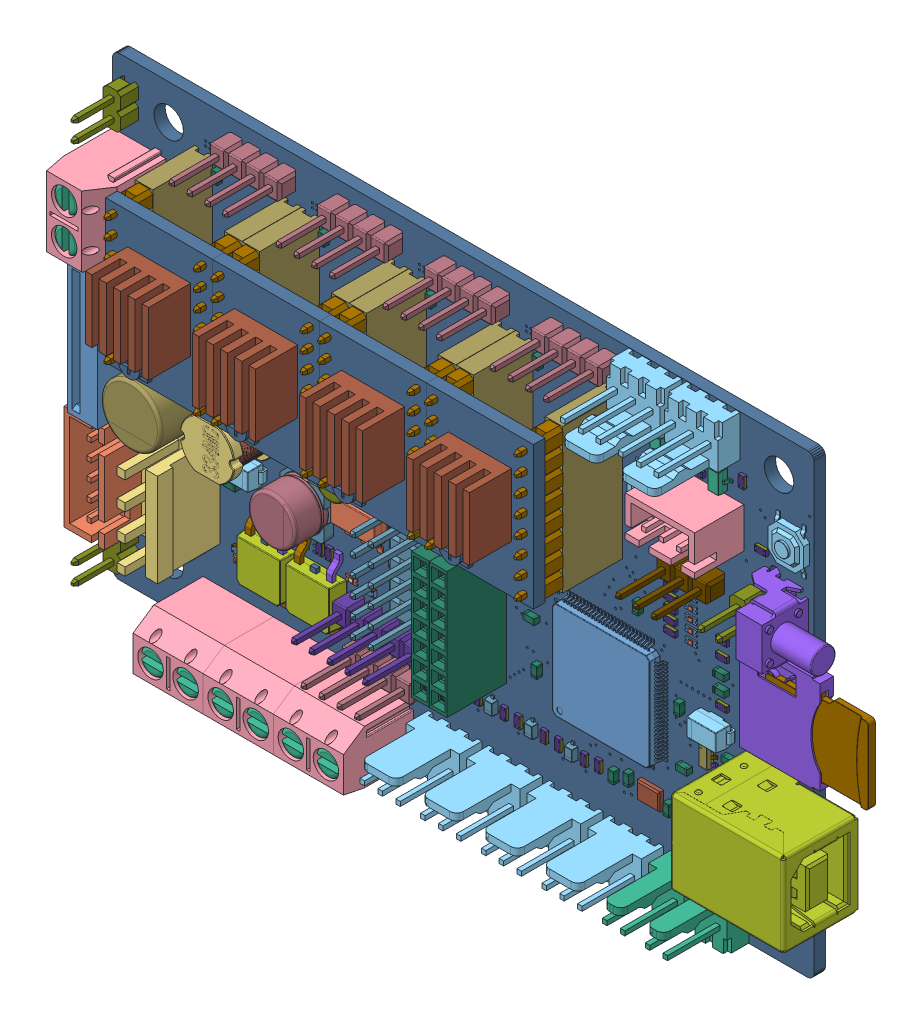
SolidWorks assembly C3D Mini v2 ASMB, configuration Default. Lengths in mm.
Overall size (109.57 66.19 23.09).
293 component instances, 83 part files, 12 mates.
Components (placement in the parent):
- C3D Mini v2 SMD-1: C3D Mini v2 SMD [Default] at (100 0.95 0) size (90.6 49.98 10.5)
  - Cut-Extrude1-1: Cut-Extrude1 [Default] at (-28.841 21.832 0) x (0 1 0) z (1 0 0) size (16.02 1.55 16.02)
  - Fillet3-1: Fillet3 [Default] at (-64.008 24.638 0) x (0 1 0) z (1 0 0) size (7.02 1.8 6.5)
  - LPattern4-1: LPattern4 [Default] at (-50.673 18.415 0) x (1 0 0) z (0 -1 0) size (2.9 1.5 2.82)
  - Cut-Extrude1-1-1: Cut-Extrude1-1 [Default] at (-70.993 28.702 0) x (0 -1 0) z (-1 0 0) size (4.9 1.5 6.03)
  - Mirror2-1: Mirror2 [Default] at (-23.241 47.879 0) x (0 1 0) z (0 0 1) size (6.5 5.08 1.52)
  - Mirror2-2: Mirror2 [Default] at (-3.187 51.423 0) x (0 1 0) z (0 0 1) size (6.5 5.08 1.52)
  - CirPattern1-1: CirPattern1 [Default] at (-12.942 54.979 0) x (0 -1 0) z (-1 0 0) size (2.9 1.5 2.82)
  - CirPattern1-2: CirPattern1 [Default] at (-21.197 54.979 0) x (0 -1 0) z (-1 0 0) size (2.9 1.5 2.82)
  - Solid1-1: Solid1 [Default] at (-67.56 17.327 0) x (-1 0 0) z (0 0 1) size (6.68 6.2 2.38)
  - Solid1-2: Solid1 [Default] at (-74.545 17.327 0) x (-1 0 0) z (0 0 1) size (6.68 6.2 2.38)
  - Solid2-1: Solid2 [Default] at (-67.56 17.327 0) x (-1 0 0) z (0 0 1) size (0.85 3.15 1.55)
  - Solid2-2: Solid2 [Default] at (-74.545 17.327 0) x (-1 0 0) z (0 0 1) size (0.85 3.15 1.55)
  - Solid3-1: Solid3 [Default] at (-74.545 17.327 0) x (-1 0 0) z (0 0 1) size (0.85 3.15 1.55)
  - Solid3-2: Solid3 [Default] at (-67.56 17.327 0) x (-1 0 0) z (0 0 1) size (0.85 3.15 1.55)
  - Solid4-1: Solid4 [Default] at (-74.545 17.327 0) x (-1 0 0) z (0 0 1) size (0.85 0.8 0.54)
  - Solid4-2: Solid4 [Default] at (-67.56 17.327 0) x (-1 0 0) z (0 0 1) size (0.85 0.8 0.54)
  - Solid5-1: Solid5 [Default] at (-74.545 17.327 0) x (-1 0 0) z (0 0 1) size (5.45 6.25 0.55)
  - Solid5-2: Solid5 [Default] at (-67.56 17.327 0) x (-1 0 0) z (0 0 1) size (5.45 6.25 0.55)
  - Solid1-1-1: Solid1-1 [Default] at (-86.995 33.93 -0.05) x (0 -1 0) z (0 0 1) size (8.5 8.5 10)
  - Solid2-1-1: Solid2-1 [Default] at (-86.995 33.93 -0.05) x (0 -1 0) z (0 0 1) size (8.5 8.5 1.4)
  - Solid3-1-1: Solid3-1 [Default] at (-86.995 33.93 -0.05) x (0 -1 0) z (0 0 1) size (3.45 1 0.7)
  - Solid4-1-1: Solid4-1 [Default] at (-86.995 33.93 -0.05) x (0 -1 0) z (0 0 1) size (3.45 1 0.7)
  - Solid1-2-1: Solid1-2 [Default] at (-61.827 31.242 -0.05) x (-1 0 0) z (0 0 1) size (4.5 4.5 5)
  - Solid2-2-1: Solid2-2 [Default] at (-61.827 31.242 -0.05) x (-1 0 0) z (0 0 1) size (4.5 4.5 1.4)
  - Solid3-2-1: Solid3-2 [Default] at (-61.827 31.242 -0.05) x (-1 0 0) z (0 0 1) size (2.25 0.75 0.7)
  - Solid4-2-1: Solid4-2 [Default] at (-61.827 31.242 -0.05) x (-1 0 0) z (0 0 1) size (2.25 0.75 0.7)
  - _I2-1: _I2 [Default] at (-62.3815 42.0396 0) x (1 0 0) z (0 0 -1) size (6.4 7.16 4.3)
  - _I3-1: _I3 [Default] at (-62.3815 42.0396 0) x (1 0 0) z (0 0 -1) size (7.69 7 7.52)
  - _I4-1: _I4 [Default] at (-62.3815 42.0396 0) x (1 0 0) z (0 0 -1) size (2.09 0.2 5.4)
  - Mirror1-1: Mirror1 [Default] at (-80.403 22.594 0) x (1 0 0) z (0 -1 0) size (5.2 2.4 2.75)
  - Mirror1-2: Mirror1 [Default] at (-72.517 32.766 0) x (-1 0 0) z (0 1 0) size (5.2 2.4 2.75)
  - Mirror1-3: Mirror1 [Default] at (-13.716 23.749 0) x (-1 0 0) z (0 1 0) size (5.2 2.4 2.75)
  - NONE-1: NONE [Default] at (-14.871 21.25 0) x (1 0 0) z (0 -1 0) size (0.54 0.52 0.44)
  - Cut-Extrude4[6]-1: Cut-Extrude4[6] [Default] at (-14.871 21.25 0) x (1 0 0) z (0 -1 0) size (0.54 0.52 0.44)
  - Cut-Extrude4[4]-1: Cut-Extrude4[4] [Default] at (-14.871 21.25 0) x (1 0 0) z (0 -1 0) size (0.54 0.52 0.44)
  - Cut-Extrude4[3]-1: Cut-Extrude4[3] [Default] at (-14.871 21.25 0) x (1 0 0) z (0 -1 0) size (0.54 0.52 0.44)
  - Cut-Extrude4[1]-1: Cut-Extrude4[1] [Default] at (-14.871 21.25 0) x (1 0 0) z (0 -1 0) size (0.54 0.52 0.44)
  - Cut-Extrude4[5]-1: Cut-Extrude4[5] [Default] at (-14.871 21.25 0) x (1 0 0) z (0 -1 0) size (0.54 0.52 0.44)
  - Fillet1-1: Fillet1 [Default] at (-14.871 21.25 0) x (1 0 0) z (0 -1 0) size (1.31 0.94 2.91)
  - Solid1-3-1: Solid1-3 [Default] at (-74.432 22.606 -0.05) size (6.8 6.8 5)
  - Solid2-3-1: Solid2-3 [Default] at (-74.432 22.606 -0.05) size (6.8 6.8 1.4)
  - Solid3-3-1: Solid3-3 [Default] at (-74.432 22.606 -0.05) size (3 0.75 0.7)
  - Solid4-3-1: Solid4-3 [Default] at (-74.432 22.606 -0.05) size (3 0.75 0.7)
  - Split Line4-1: Split Line4 [Default] at (-17.399 39.243 0) x (1 0 0) z (0 -1 0) size (1.6 0.18 0.8)
  - Boss-Extrude2-1: Boss-Extrude2 [Default] at (-17.399 39.243 0) x (1 0 0) z (0 -1 0) size (0.6 0.1 0.5)
  - Split Line4-1-1: Split Line4-1 [Default] at (-17.399 32.258 0) x (1 0 0) z (0 -1 0) size (1.6 0.18 0.8)
  - Split Line4-1-2: Split Line4-1 [Default] at (-17.399 33.655 0) x (1 0 0) z (0 -1 0) size (1.6 0.18 0.8)
  - Split Line4-1-3: Split Line4-1 [Default] at (-17.399 35.052 0) x (1 0 0) z (0 -1 0) size (1.6 0.18 0.8)
  - Split Line4-1-4: Split Line4-1 [Default] at (-17.399 37.846 0) x (1 0 0) z (0 -1 0) size (1.6 0.18 0.8)
  - Split Line4-1-5: Split Line4-1 [Default] at (-17.399 36.449 0) x (1 0 0) z (0 -1 0) size (1.6 0.18 0.8)
  - Split Line4-1-6: Split Line4-1 [Default] at (-8.521 39.993 0) x (1 0 0) z (0 -1 0) size (1.6 0.18 0.8)
  - Boss-Extrude2-1-1: Boss-Extrude2-1 [Default] at (-8.521 39.993 0) x (1 0 0) z (0 -1 0) size (0.6 0.1 0.5)
  - Boss-Extrude2-1-2: Boss-Extrude2-1 [Default] at (-17.399 36.449 0) x (1 0 0) z (0 -1 0) size (0.6 0.1 0.5)
  - Boss-Extrude2-1-3: Boss-Extrude2-1 [Default] at (-17.399 37.846 0) x (1 0 0) z (0 -1 0) size (0.6 0.1 0.5)
  - Boss-Extrude2-1-4: Boss-Extrude2-1 [Default] at (-17.399 35.052 0) x (1 0 0) z (0 -1 0) size (0.6 0.1 0.5)
  - Boss-Extrude2-1-5: Boss-Extrude2-1 [Default] at (-17.399 33.655 0) x (1 0 0) z (0 -1 0) size (0.6 0.1 0.5)
  - Boss-Extrude2-1-6: Boss-Extrude2-1 [Default] at (-17.399 32.258 0) x (1 0 0) z (0 -1 0) size (0.6 0.1 0.5)
  - Boss-Extrude3-1: Boss-Extrude3 [Default] at (-49.415 44.184 0) x (-1 0 0) z (0 1 0) size (7 7.7 6.6)
  - Boss-Extrude3-2: Boss-Extrude3 [Default] at (-64.655 44.184 0) x (-1 0 0) z (0 1 0) size (7 7.7 6.6)
  - Boss-Extrude3-3: Boss-Extrude3 [Default] at (-34.175 44.184 0) x (-1 0 0) z (0 1 0) size (7 7.7 6.6)
  - Boss-Extrude3-4: Boss-Extrude3 [Default] at (-79.895 44.184 0) x (-1 0 0) z (0 1 0) size (7 7.7 6.6)
  - Solid1-4-1: Solid1-4 [Default] at (-13.686 12.407 0) x (-1 0 0) z (0 0 1) size (0.5 0.45 0.55)
  - Solid2-4-1: Solid2-4 [Default] at (-13.686 12.407 0) x (-1 0 0) z (0 0 1) size (0.5 0.45 0.55)
  - Solid3-4-1: Solid3-4 [Default] at (-13.686 12.407 0) x (-1 0 0) z (0 0 1) size (0.5 0.45 0.55)
  - Solid4-4-1: Solid4-4 [Default] at (-13.686 12.407 0) x (-1 0 0) z (0 0 1) size (0.5 0.45 0.55)
  - Solid5-1-1: Solid5-1 [Default] at (-13.686 12.407 0) x (-1 0 0) z (0 0 1) size (3.35 1.69 0.49)
  - Solid6-1: Solid6 [Default] at (-13.686 12.407 0) x (-1 0 0) z (0 0 1) size (3.18 1.09 0.08)
  - Solid7-1: Solid7 [Default] at (-13.686 12.407 0) x (-1 0 0) z (0 0 1) size (0.72 0.45 0.55)
  - Solid8-1: Solid8 [Default] at (-13.686 12.407 0) x (-1 0 0) z (0 0 1) size (0.72 0.45 0.55)
  - Solid9-1: Solid9 [Default] at (-13.686 12.407 0) x (-1 0 0) z (0 0 1) size (0.73 0.45 0.55)
  - Solid10-1: Solid10 [Default] at (-13.686 12.407 0) x (-1 0 0) z (0 0 1) size (0.73 0.45 0.55)
  - Boss-Extrude2-2-1: Boss-Extrude2-2 [Default] at (-51.423 10.299 0) x (0 -1 0) z (-1 0 0) size (2.5 0.8 1.25)
  - Boss-Extrude2-2-2: Boss-Extrude2-2 [Default] at (-45.708 10.299 0) x (0 -1 0) z (-1 0 0) size (2.5 0.8 1.25)
  - Boss-Extrude2-2-3: Boss-Extrude2-2 [Default] at (-34.278 10.299 0) x (0 -1 0) z (-1 0 0) size (2.5 0.8 1.25)
  - Boss-Extrude2-2-4: Boss-Extrude2-2 [Default] at (-39.993 10.299 0) x (0 -1 0) z (-1 0 0) size (2.5 0.8 1.25)
  - Mirror1-1-1: Mirror1-1 [Default] at (-12.839 30.722 0) x (1 0 0) z (0 -1 0) size (1.6 0.82 0.82)
  - Mirror1-1-2: Mirror1-1 [Default] at (-18.796 23.622 0) x (0 1 0) z (1 0 0) size (1.6 0.82 0.82)
  - Mirror1-1-3: Mirror1-1 [Default] at (-20.32 10.414 0) x (0 1 0) z (1 0 0) size (1.6 0.82 0.82)
  - Mirror1-1-4: Mirror1-1 [Default] at (-26.047 11.291 0) x (0 1 0) z (1 0 0) size (1.6 0.82 0.82)
  - Mirror1-1-5: Mirror1-1 [Default] at (-13.589 7.874 0) x (0 -1 0) z (-1 0 0) size (1.6 0.82 0.82)
  - Mirror1-1-6: Mirror1-1 [Default] at (-61.2895 27.8645 0) x (0 1 0) z (1 0 0) size (1.6 0.82 0.82)
  - Mirror1-1-7: Mirror1-1 [Default] at (-28.182 10.553 0) x (0 1 0) z (1 0 0) size (1.6 0.82 0.82)
  - Mirror1-1-8: Mirror1-1 [Default] at (-53.479 39.485 0) x (1 0 0) z (0 -1 0) size (1.6 0.82 0.82)
  - Mirror1-1-9: Mirror1-1 [Default] at (-39.128 18.0982 0) x (0 1 0) z (1 0 0) size (1.6 0.82 0.82)
  - Mirror1-1-10: Mirror1-1 [Default] at (-15.621 7.874 0) x (0 -1 0) z (-1 0 0) size (1.6 0.82 0.82)
  - Mirror1-1-11: Mirror1-1 [Default] at (-11.684 14.605 0) x (1 0 0) z (0 -1 0) size (1.6 0.82 0.82)
  - Mirror1-1-12: Mirror1-1 [Default] at (-69.481 56.249 0) x (0 -1 0) z (-1 0 0) size (1.6 0.82 0.82)
  - Mirror1-1-13: Mirror1-1 [Default] at (-18.796 10.668 0) x (0 1 0) z (1 0 0) size (1.6 0.82 0.82)
  - Mirror1-1-14: Mirror1-1 [Default] at (-39.89 24.1688 0) x (1 0 0) z (0 -1 0) size (1.6 0.82 0.82)
  - Mirror1-1-15: Mirror1-1 [Default] at (-33.6035 33.135 0) x (0 1 0) z (1 0 0) size (1.6 0.82 0.82)
  - Mirror1-1-16: Mirror1-1 [Default] at (-11.684 20.701 0) x (1 0 0) z (0 -1 0) size (1.6 0.82 0.82)
  - Mirror1-1-17: Mirror1-1 [Default] at (-18.149 16.4472 0) x (1 0 0) z (0 -1 0) size (1.6 0.82 0.82)
  - Mirror1-1-18: Mirror1-1 [Default] at (-82.55 19.304 0) x (1 0 0) z (0 -1 0) size (1.6 0.82 0.82)
  - Mirror1-1-19: Mirror1-1 [Default] at (-24.7135 33.135 0) x (0 1 0) z (1 0 0) size (1.6 0.82 0.82)
  - Mirror1-1-20: Mirror1-1 [Default] at (-50.8 15.494 0) x (1 0 0) z (0 -1 0) size (1.6 0.82 0.82)
  - Mirror1-1-21: Mirror1-1 [Default] at (-39.001 56.249 0) x (0 -1 0) z (-1 0 0) size (1.6 0.82 0.82)
  - Mirror1-1-22: Mirror1-1 [Default] at (-83.959 39.485 0) x (1 0 0) z (0 -1 0) size (1.6 0.82 0.82)
  - Mirror1-1-23: Mirror1-1 [Default] at (-84.721 56.249 0) x (0 -1 0) z (-1 0 0) size (1.6 0.82 0.82)
  - Mirror1-1-24: Mirror1-1 [Default] at (-68.719 39.485 0) x (1 0 0) z (0 -1 0) size (1.6 0.82 0.82)
  - Mirror1-1-25: Mirror1-1 [Default] at (-12.839 28.69 0) x (1 0 0) z (0 -1 0) size (1.6 0.82 0.82)
  - Mirror1-1-26: Mirror1-1 [Default] at (-38.239 39.485 0) x (1 0 0) z (0 -1 0) size (1.6 0.82 0.82)
  - Mirror1-1-27: Mirror1-1 [Default] at (-54.241 56.249 0) x (0 -1 0) z (-1 0 0) size (1.6 0.82 0.82)
  - Boss-Extrude3-1-1: Boss-Extrude3-1 [Default] at (-34.81 39.885 0) x (1 0 0) z (0 -1 0) size (1.54 0.39 0.8)
  - Boss-Extrude3-1-2: Boss-Extrude3-1 [Default] at (-12.839 27.058 0) x (1 0 0) z (0 -1 0) size (1.54 0.39 0.8)
  - Boss-Extrude3-1-3: Boss-Extrude3-1 [Default] at (-47.213 10.299 0) x (0 -1 0) z (-1 0 0) size (1.54 0.39 0.8)
  - Boss-Extrude3-1-4: Boss-Extrude3-1 [Default] at (-80.53 39.885 0) x (1 0 0) z (0 -1 0) size (1.54 0.39 0.8)
  - Boss-Extrude3-1-5: Boss-Extrude3-1 [Default] at (-20.193 39.643 0) x (1 0 0) z (0 -1 0) size (1.54 0.39 0.8)
  - Boss-Extrude3-1-6: Boss-Extrude3-1 [Default] at (-12.839 33.154 0) x (1 0 0) z (0 -1 0) size (1.54 0.39 0.8)
  - Boss-Extrude3-1-7: Boss-Extrude3-1 [Default] at (-9.5822 55.88 0) x (0 -1 0) z (-1 0 0) size (1.54 0.39 0.8)
  - Boss-Extrude3-1-8: Boss-Extrude3-1 [Default] at (-49.384 22.225 0) x (0 -1 0) z (-1 0 0) size (1.54 0.39 0.8)
  - Boss-Extrude3-1-9: Boss-Extrude3-1 [Default] at (-12.839 35.186 0) x (1 0 0) z (0 -1 0) size (1.54 0.39 0.8)
  - Boss-Extrude3-1-10: Boss-Extrude3-1 [Default] at (-68.434 17.526 0) x (0 -1 0) z (-1 0 0) size (1.54 0.39 0.8)
  - Boss-Extrude3-1-11: Boss-Extrude3-1 [Default] at (-20.193 38.246 0) x (1 0 0) z (0 -1 0) size (1.54 0.39 0.8)
  - Boss-Extrude3-1-12: Boss-Extrude3-1 [Default] at (-46.621 39.25 0) x (1 0 0) z (0 -1 0) size (1.54 0.39 0.8)
  - Boss-Extrude3-1-13: Boss-Extrude3-1 [Default] at (-61.861 39.25 0) x (1 0 0) z (0 -1 0) size (1.54 0.39 0.8)
  - Boss-Extrude3-1-14: Boss-Extrude3-1 [Default] at (-41.498 10.299 0) x (0 -1 0) z (-1 0 0) size (1.54 0.39 0.8)
  - Boss-Extrude3-1-15: Boss-Extrude3-1 [Default] at (-31.381 39.25 0) x (1 0 0) z (0 -1 0) size (1.54 0.39 0.8)
  - Boss-Extrude3-1-16: Boss-Extrude3-1 [Default] at (-52.928 10.299 0) x (0 -1 0) z (-1 0 0) size (1.54 0.39 0.8)
  - Boss-Extrude3-1-17: Boss-Extrude3-1 [Default] at (-49.245 10.299 0) x (0 -1 0) z (-1 0 0) size (1.54 0.39 0.8)
  - Boss-Extrude3-1-18: Boss-Extrude3-1 [Default] at (-24.499 54.363 0) x (1 0 0) z (0 -1 0) size (1.54 0.39 0.8)
  - Boss-Extrude3-1-19: Boss-Extrude3-1 [Default] at (-76.7271 17.526 0) x (0 -1 0) z (-1 0 0) size (1.54 0.39 0.8)
  - Boss-Extrude3-1-20: Boss-Extrude3-1 [Default] at (-20.193 32.658 0) x (1 0 0) z (0 -1 0) size (1.54 0.39 0.8)
  - Boss-Extrude3-1-21: Boss-Extrude3-1 [Default] at (-11.684 12.973 0) x (1 0 0) z (0 -1 0) size (1.54 0.39 0.8)
  - Boss-Extrude3-1-22: Boss-Extrude3-1 [Default] at (-6.489 44.965 0) x (1 0 0) z (0 -1 0) size (1.54 0.39 0.8)
  - Boss-Extrude3-1-23: Boss-Extrude3-1 [Default] at (-20.193 35.452 0) x (1 0 0) z (0 -1 0) size (1.54 0.39 0.8)
  - Boss-Extrude3-1-24: Boss-Extrude3-1 [Default] at (-20.193 34.055 0) x (1 0 0) z (0 -1 0) size (1.54 0.39 0.8)
  - Boss-Extrude3-1-25: Boss-Extrude3-1 [Default] at (-24.499 56.395 0) x (1 0 0) z (0 -1 0) size (1.54 0.39 0.8)
  - Boss-Extrude3-1-26: Boss-Extrude3-1 [Default] at (-22.352 44.088 0) x (1 0 0) z (0 -1 0) size (1.54 0.39 0.8)
  - Boss-Extrude3-1-27: Boss-Extrude3-1 [Default] at (-32.1 10.299 0) x (0 -1 0) z (-1 0 0) size (1.54 0.39 0.8)
  - Boss-Extrude3-1-28: Boss-Extrude3-1 [Default] at (-65.29 39.885 0) x (1 0 0) z (0 -1 0) size (1.54 0.39 0.8)
  - Boss-Extrude3-1-29: Boss-Extrude3-1 [Default] at (-50.05 39.885 0) x (1 0 0) z (0 -1 0) size (1.54 0.39 0.8)
  - Boss-Extrude3-1-30: Boss-Extrude3-1 [Default] at (-30.068 10.553 0) x (0 -1 0) z (-1 0 0) size (1.54 0.39 0.8)
  - Boss-Extrude3-1-31: Boss-Extrude3-1 [Default] at (-75.419 17.526 0) x (0 -1 0) z (-1 0 0) size (1.54 0.39 0.8)
  - Boss-Extrude3-1-32: Boss-Extrude3-1 [Default] at (-43.53 10.299 0) x (0 -1 0) z (-1 0 0) size (1.54 0.39 0.8)
  - Boss-Extrude3-1-33: Boss-Extrude3-1 [Default] at (-11.684 17.037 0) x (1 0 0) z (0 -1 0) size (1.54 0.39 0.8)
  - Boss-Extrude3-1-34: Boss-Extrude3-1 [Default] at (-8.521 39.123 0) x (1 0 0) z (0 -1 0) size (1.54 0.39 0.8)
  - Boss-Extrude3-1-35: Boss-Extrude3-1 [Default] at (-69.7421 17.526 0) x (0 -1 0) z (-1 0 0) size (1.54 0.39 0.8)
  - Boss-Extrude3-1-36: Boss-Extrude3-1 [Default] at (-16.244 56.3315 0) x (1 0 0) z (0 -1 0) size (1.54 0.39 0.8)
  - Boss-Extrude3-1-37: Boss-Extrude3-1 [Default] at (-37.815 10.299 0) x (0 -1 0) z (-1 0 0) size (1.54 0.39 0.8)
  - Boss-Extrude3-1-38: Boss-Extrude3-1 [Default] at (-20.193 36.849 0) x (1 0 0) z (0 -1 0) size (1.54 0.39 0.8)
  - Boss-Extrude3-1-39: Boss-Extrude3-1 [Default] at (-35.783 10.299 0) x (0 -1 0) z (-1 0 0) size (1.54 0.39 0.8)
  - Boss-Extrude3-1-40: Boss-Extrude3-1 [Default] at (-77.101 39.25 0) x (1 0 0) z (0 -1 0) size (1.54 0.39 0.8)
  - Boss-Extrude3-1-41: Boss-Extrude3-1 [Default] at (-7.251 49.156 0) x (1 0 0) z (0 -1 0) size (1.54 0.39 0.8)
  - Boss-Extrude3-1-42: Boss-Extrude3-1 [Default] at (-16.244 54.2995 0) x (1 0 0) z (0 -1 0) size (1.54 0.39 0.8)
  - Boss-Extrude3-1-43: Boss-Extrude3-1 [Default] at (-11.684 19.069 0) x (1 0 0) z (0 -1 0) size (1.54 0.39 0.8)
  - Split Line1-1: Split Line1 [Default] at (-11.684 12.973 0) x (1 0 0) z (0 -1 0) size (1.6 0.45 0.8)
  - Split Line1-2: Split Line1 [Default] at (-11.684 19.069 0) x (1 0 0) z (0 -1 0) size (1.6 0.45 0.8)
  - Split Line1-3: Split Line1 [Default] at (-37.815 10.299 0) x (0 -1 0) z (-1 0 0) size (1.6 0.45 0.8)
  - Split Line1-4: Split Line1 [Default] at (-24.499 54.363 0) x (1 0 0) z (0 -1 0) size (1.6 0.45 0.8)
  - Split Line1-5: Split Line1 [Default] at (-20.193 34.055 0) x (1 0 0) z (0 -1 0) size (1.6 0.45 0.8)
  - Split Line1-6: Split Line1 [Default] at (-35.783 10.299 0) x (0 -1 0) z (-1 0 0) size (1.6 0.45 0.8)
  - Split Line1-7: Split Line1 [Default] at (-7.251 49.156 0) x (1 0 0) z (0 -1 0) size (1.6 0.45 0.8)
  - Split Line1-8: Split Line1 [Default] at (-16.244 56.3315 0) x (1 0 0) z (0 -1 0) size (1.6 0.45 0.8)
  - Split Line1-9: Split Line1 [Default] at (-16.244 54.2995 0) x (1 0 0) z (0 -1 0) size (1.6 0.45 0.8)
  - Split Line1-10: Split Line1 [Default] at (-20.193 36.849 0) x (1 0 0) z (0 -1 0) size (1.6 0.45 0.8)
  - Split Line1-11: Split Line1 [Default] at (-61.861 39.25 0) x (1 0 0) z (0 -1 0) size (1.6 0.45 0.8)
  - Split Line1-12: Split Line1 [Default] at (-6.489 44.965 0) x (1 0 0) z (0 -1 0) size (1.6 0.45 0.8)
  - Split Line1-13: Split Line1 [Default] at (-20.193 38.246 0) x (1 0 0) z (0 -1 0) size (1.6 0.45 0.8)
  - Split Line1-14: Split Line1 [Default] at (-12.839 27.058 0) x (1 0 0) z (0 -1 0) size (1.6 0.45 0.8)
  - Split Line1-15: Split Line1 [Default] at (-69.7421 17.526 0) x (0 -1 0) z (-1 0 0) size (1.6 0.45 0.8)
  - Split Line1-16: Split Line1 [Default] at (-20.193 32.658 0) x (1 0 0) z (0 -1 0) size (1.6 0.45 0.8)
  - Split Line1-17: Split Line1 [Default] at (-22.352 44.088 0) x (1 0 0) z (0 -1 0) size (1.6 0.45 0.8)
  - Split Line1-18: Split Line1 [Default] at (-49.384 22.225 0) x (0 -1 0) z (-1 0 0) size (1.6 0.45 0.8)
  - Split Line1-19: Split Line1 [Default] at (-65.29 39.885 0) x (1 0 0) z (0 -1 0) size (1.6 0.45 0.8)
  - Split Line1-20: Split Line1 [Default] at (-75.419 17.526 0) x (0 -1 0) z (-1 0 0) size (1.6 0.45 0.8)
  - Split Line1-21: Split Line1 [Default] at (-77.101 39.25 0) x (1 0 0) z (0 -1 0) size (1.6 0.45 0.8)
  - Split Line1-22: Split Line1 [Default] at (-34.81 39.885 0) x (1 0 0) z (0 -1 0) size (1.6 0.45 0.8)
  - Split Line1-23: Split Line1 [Default] at (-20.193 35.452 0) x (1 0 0) z (0 -1 0) size (1.6 0.45 0.8)
  - Split Line1-24: Split Line1 [Default] at (-50.05 39.885 0) x (1 0 0) z (0 -1 0) size (1.6 0.45 0.8)
  - Split Line1-25: Split Line1 [Default] at (-9.5822 55.88 0) x (0 -1 0) z (-1 0 0) size (1.6 0.45 0.8)
  - Split Line1-26: Split Line1 [Default] at (-43.53 10.299 0) x (0 -1 0) z (-1 0 0) size (1.6 0.45 0.8)
  - Split Line1-27: Split Line1 [Default] at (-46.621 39.25 0) x (1 0 0) z (0 -1 0) size (1.6 0.45 0.8)
  - Split Line1-28: Split Line1 [Default] at (-41.498 10.299 0) x (0 -1 0) z (-1 0 0) size (1.6 0.45 0.8)
  - Split Line1-29: Split Line1 [Default] at (-8.521 39.123 0) x (1 0 0) z (0 -1 0) size (1.6 0.45 0.8)
  - Split Line1-30: Split Line1 [Default] at (-68.434 17.526 0) x (0 -1 0) z (-1 0 0) size (1.6 0.45 0.8)
  - Split Line1-31: Split Line1 [Default] at (-52.928 10.299 0) x (0 -1 0) z (-1 0 0) size (1.6 0.45 0.8)
  - Split Line1-32: Split Line1 [Default] at (-24.499 56.395 0) x (1 0 0) z (0 -1 0) size (1.6 0.45 0.8)
  - Split Line1-33: Split Line1 [Default] at (-47.213 10.299 0) x (0 -1 0) z (-1 0 0) size (1.6 0.45 0.8)
  - Split Line1-34: Split Line1 [Default] at (-20.193 39.643 0) x (1 0 0) z (0 -1 0) size (1.6 0.45 0.8)
  - Split Line1-35: Split Line1 [Default] at (-31.381 39.25 0) x (1 0 0) z (0 -1 0) size (1.6 0.45 0.8)
  - Split Line1-36: Split Line1 [Default] at (-76.7271 17.526 0) x (0 -1 0) z (-1 0 0) size (1.6 0.45 0.8)
  - Split Line1-37: Split Line1 [Default] at (-49.245 10.299 0) x (0 -1 0) z (-1 0 0) size (1.6 0.45 0.8)
  - Split Line1-38: Split Line1 [Default] at (-32.1 10.299 0) x (0 -1 0) z (-1 0 0) size (1.6 0.45 0.8)
  - Split Line1-39: Split Line1 [Default] at (-12.839 33.154 0) x (1 0 0) z (0 -1 0) size (1.6 0.45 0.8)
  - Split Line1-40: Split Line1 [Default] at (-30.068 10.553 0) x (0 -1 0) z (-1 0 0) size (1.6 0.45 0.8)
  - Split Line1-41: Split Line1 [Default] at (-11.684 17.037 0) x (1 0 0) z (0 -1 0) size (1.6 0.45 0.8)
  - Split Line1-42: Split Line1 [Default] at (-80.53 39.885 0) x (1 0 0) z (0 -1 0) size (1.6 0.45 0.8)
  - Split Line1-43: Split Line1 [Default] at (-12.839 35.186 0) x (1 0 0) z (0 -1 0) size (1.6 0.45 0.8)
  - Boss-Extrude3-2-1: Boss-Extrude3-2 [Default] at (-59.417 21.082 0) x (0 -1 0) z (-1 0 0) size (1.54 0.39 0.8)
  - Boss-Extrude3-2-2: Boss-Extrude3-2 [Default] at (-63.119 16.148 0) x (1 0 0) z (0 -1 0) size (1.54 0.39 0.8)
  - Boss-Extrude3-2-3: Boss-Extrude3-2 [Default] at (-59.417 24.638 0) x (0 -1 0) z (-1 0 0) size (1.54 0.39 0.8)
  - Boss-Extrude3-2-4: Boss-Extrude3-2 [Default] at (-81.788 11.83 0) x (1 0 0) z (0 -1 0) size (1.54 0.39 0.8)
  - Split Line1-1-1: Split Line1-1 [Default] at (-59.417 24.638 0) x (0 -1 0) z (-1 0 0) size (1.6 0.45 0.8)
  - Split Line1-1-2: Split Line1-1 [Default] at (-59.417 21.082 0) x (0 -1 0) z (-1 0 0) size (1.6 0.45 0.8)
  - Split Line1-1-3: Split Line1-1 [Default] at (-63.119 16.148 0) x (1 0 0) z (0 -1 0) size (1.6 0.45 0.8)
  - Split Line1-1-4: Split Line1-1 [Default] at (-81.788 11.83 0) x (1 0 0) z (0 -1 0) size (1.6 0.45 0.8)
  - Split Line4-2-1: Split Line4-2 [Default] at (-81.788 10.16 0) x (1 0 0) z (0 -1 0) size (1.6 0.18 0.8)
  - Split Line4-2-2: Split Line4-2 [Default] at (-65.786 15.748 0) x (1 0 0) z (0 -1 0) size (1.6 0.18 0.8)
  - Boss-Extrude2-3-1: Boss-Extrude2-3 [Default] at (-81.788 10.16 0) x (1 0 0) z (0 -1 0) size (0.6 0.1 0.5)
  - Boss-Extrude2-3-2: Boss-Extrude2-3 [Default] at (-65.786 15.748 0) x (1 0 0) z (0 -1 0) size (0.6 0.1 0.5)
- DG301-5.0-02 (OPTION 1)-1: DG301-5.0-02 (OPTION 1) [Default] at (3.11 52.82 0) x (0 -1 0) z (0 0 1) size (10.6 7.6 14.4)
  - DG301-5.0-02-body-1: DG301-5.0-02-body [Default] at origin size (10.6 7.6 10)
  - DG301-5.0-pin-1: DG301-5.0-pin [Default] at (0 0.5 2.85) size (3.9 4 9.9)
  - DG301-5.0-pin-2: DG301-5.0-pin [Default] at (5 0.5 2.85) size (3.9 4 9.9)
  - DG301-5.0-screw-1: DG301-5.0-screw [Default] at (5 0 4) size (3.6 3.6 5.84)
  - DG301-5.0-screw-2: DG301-5.0-screw [Default] at (0 0 4) size (3.6 3.6 5.84)
  - DG301-5.0-wire_prot-1: DG301-5.0-wire_prot [Default] at (5 0 5.5) size (3.9 5.45 2.85)
  - DG301-5.0-wire_prot-2: DG301-5.0-wire_prot [Default] at (0 0 5.5) size (3.9 5.45 2.85)
- DG301-5.0-02 (OPTION 1)-1-1: DG301-5.0-02 (OPTION 1)-1 [Default] at (15.42 1.91 0) size (10.6 7.6 14.4)
  - DG301-5.0-02-body-1: DG301-5.0-02-body [Default] at origin size (10.6 7.6 10)
  - DG301-5.0-pin-1: DG301-5.0-pin [Default] at (0 0.5 2.85) size (3.9 4 9.9)
  - DG301-5.0-pin-2: DG301-5.0-pin [Default] at (5 0.5 2.85) size (3.9 4 9.9)
  - DG301-5.0-screw-1: DG301-5.0-screw [Default] at (0 0 4) size (3.6 3.6 5.84)
  - DG301-5.0-screw-2: DG301-5.0-screw [Default] at (5 0 4) size (3.6 3.6 5.84)
  - DG301-5.0-wire_prot-1: DG301-5.0-wire_prot [Default] at (0 0 5.5) size (3.9 5.45 2.85)
  - DG301-5.0-wire_prot-2: DG301-5.0-wire_prot [Default] at (5 0 5.5) size (3.9 5.45 2.85)
- DG301-5.0-02 (OPTION 1)-2-1: DG301-5.0-02 (OPTION 1)-2 [Default] at (25.42 1.91 0) size (10.6 7.6 14.4)
  - DG301-5.0-02-body-1: DG301-5.0-02-body [Default] at origin size (10.6 7.6 10)
  - DG301-5.0-pin-1: DG301-5.0-pin [Default] at (0 0.5 2.85) size (3.9 4 9.9)
  - DG301-5.0-pin-2: DG301-5.0-pin [Default] at (5 0.5 2.85) size (3.9 4 9.9)
  - DG301-5.0-screw-1: DG301-5.0-screw [Default] at (0 0 4) size (3.6 3.6 5.84)
  - DG301-5.0-screw-2: DG301-5.0-screw [Default] at (5 0 4) size (3.6 3.6 5.84)
  - DG301-5.0-wire_prot-1: DG301-5.0-wire_prot [Default] at (5 0 5.5) size (3.9 5.45 2.85)
  - DG301-5.0-wire_prot-2: DG301-5.0-wire_prot [Default] at (0 0 5.5) size (3.9 5.45 2.85)
- DG301-5.0-02 (OPTION 1)-3-1: DG301-5.0-02 (OPTION 1)-3 [Default] at (35.42 1.91 0) size (10.6 7.6 14.4)
  - DG301-5.0-02-body-1: DG301-5.0-02-body [Default] at origin size (10.6 7.6 10)
  - DG301-5.0-pin-1: DG301-5.0-pin [Default] at (5 0.5 2.85) size (3.9 4 9.9)
  - DG301-5.0-pin-2: DG301-5.0-pin [Default] at (0 0.5 2.85) size (3.9 4 9.9)
  - DG301-5.0-screw-1: DG301-5.0-screw [Default] at (5 0 4) size (3.6 3.6 5.84)
  - DG301-5.0-screw-2: DG301-5.0-screw [Default] at (0 0 4) size (3.6 3.6 5.84)
  - DG301-5.0-wire_prot-1: DG301-5.0-wire_prot [Default] at (5 0 5.5) size (3.9 5.45 2.85)
  - DG301-5.0-wire_prot-2: DG301-5.0-wire_prot [Default] at (0 0 5.5) size (3.9 5.45 2.85)
- SD SLot Assembly-1: SD SLot Assembly [Default] at (68.9232 25.4319 -11.7384) x (-1 0 0) z (0 0 1) size (19.43 14.95 2.45)
  - SD Slot-1: SD Slot [Default] at (-32.2702 -6.7777 11.7384) size (12.6 14.95 2.45)
  - micro_sd_card-1: micro_sd_card [Default] at (-40.6508 -12.1921 12.5884) x (1 0 0) z (0 -1 0) size (15 1.05 11.24)
- c3d mini Board v2-1: c3d mini Board v2 [Default] at (100 1 -1.6) size (100 65 1.6)
- 12MHZ Crystal PN X322512MMB4SC-1: 12MHZ Crystal PN X322512MMB4SC [Default] at (76.95 11.61 0) x (1 0 0) z (0 -1 0) size (3.2 0.7 2.5)
- female_header_a-bl254-eg-g08d-1: female_header_a-bl254-eg-g08d [Default] at (40.93 48.74 0) x (0 1 0) z (1 0 0) size (20.57 11.65 2.5)
- female_header_a-bl254-eg-g08d-2: female_header_a-bl254-eg-g08d [Default] at (56.17 48.74 0) x (0 1 0) z (1 0 0) size (20.57 11.65 2.5)
- female_header_a-bl254-eg-g08d-3: female_header_a-bl254-eg-g08d [Default] at (25.69 48.74 0) x (0 1 0) z (1 0 0) size (20.57 11.65 2.5)
- female_header_a-bl254-eg-g08d-4: female_header_a-bl254-eg-g08d [Default] at (28.23 48.74 0) x (0 1 0) z (1 0 0) size (20.57 11.65 2.5)
- female_header_a-bl254-eg-g08d-5: female_header_a-bl254-eg-g08d [Default] at (58.71 48.74 0) x (0 1 0) z (1 0 0) size (20.57 11.65 2.5)
- female_header_a-bl254-eg-g08d-6: female_header_a-bl254-eg-g08d [Default] at (43.47 48.74 0) x (0 1 0) z (1 0 0) size (20.57 11.65 2.5)
- female_header_a-bl254-eg-g08d-7: female_header_a-bl254-eg-g08d [Default] at (71.41 48.74 0) x (0 1 0) z (1 0 0) size (20.57 11.65 2.5)
- female_header_a-bl254-eg-g08d-8: female_header_a-bl254-eg-g08d [Default] at (12.99 48.74 0) x (0 1 0) z (1 0 0) size (20.57 11.65 2.5)
- Pin Header 1x4 TH Pitch 2.54mm-1: Pin Header 1x4 TH Pitch 2.54mm [Default] at (17.6898 61.95 -0.0015) x (1 0 -0.000037) z (0.000037 0 1) size (10.16 2.54 12.7)
- Pin Header 1x4 TH Pitch 2.54mm-2: Pin Header 1x4 TH Pitch 2.54mm [Default] at (32.9298 61.95 -0.0015) x (1 0 -0.000037) z (0.000037 0 1) size (10.16 2.54 12.7)
- Pin Header 1x4 TH Pitch 2.54mm-3: Pin Header 1x4 TH Pitch 2.54mm [Default] at (36.4998 9.26 -0.0015) x (1 0 -0.000037) z (0.000037 0 1) size (10.16 2.54 12.7)
- Pin Header 1x4 TH Pitch 2.54mm-4: Pin Header 1x4 TH Pitch 2.54mm [Default] at (48.1698 61.95 -0.0015) x (1 0 -0.000037) z (0.000037 0 1) size (10.16 2.54 12.7)
- Pin Header 1x4 TH Pitch 2.54mm-5: Pin Header 1x4 TH Pitch 2.54mm [Default] at (63.4098 61.95 -0.0015) x (1 0 -0.000037) z (0.000037 0 1) size (10.16 2.54 12.7)
- Pin Header 2x6 TH Pitch 2.54mm-1: Pin Header 2x6 TH Pitch 2.54mm [Default] at (44.75 31.4802 -0.0009) x (0 -1 -0.000037) z (0 -0.000037 1) size (15.24 5.08 12.7)
- female_header_a-bl254-eg-g07d-1: female_header_a-bl254-eg-g07d [Default] at (52.38 25.13 0) x (0 1 0) z (1 0 0) size (18.03 11.65 2.5)
- female_header_a-bl254-eg-g07d-2: female_header_a-bl254-eg-g07d [Default] at (54.91 25.13 0) x (0 1 0) z (1 0 0) size (18.03 11.65 2.5)
- pin_header_aw140-eg-g02d-1: pin_header_aw140-eg-g02d [Default] at (2.46 13.19 0) x (0 1 0) z (-1 0 0) size (5.08 11.2 2.5)
- pin_header_aw140-eg-g02d-2: pin_header_aw140-eg-g02d [Default] at (85.39 43.24 0) x (-1 0 0) z (0 -1 0) size (5.08 11.2 2.5)
- pin_header_aw140-eg-g02d-3: pin_header_aw140-eg-g02d [Default] at (2.46 67.8 0) x (0 1 0) z (-1 0 0) size (5.08 11.2 2.5)
- Pin Header 1x5 TH Pitch 2.54mm-1: Pin Header 1x5 TH Pitch 2.54mm [Default] at (35.0998 14.08 -0.0014) x (1 0 -0.000037) z (0.000037 0 1) size (12.7 2.54 12.7)
- Pin Header 1x3 TH Pitch 2.54mm-1: Pin Header 1x3 TH Pitch 2.54mm [Default] at (81.3298 42.78 -0.0012) x (1 0 -0.000037) z (0.000037 0 1) size (7.62 2.54 12.7)
- c-1-84534-2-e-3d (FFC1)-1: c-1-84534-2-e-3d (FFC1) [Default] at (3.505 34.165 7.8) x (0 -1 0) z (0 0 1) size (18.75 4.8 11)
- B5B-XH-A (U$12)-1: B5B-XH-A (U$12) [Default] at (2.95 17.04 0) x (0 1 0) z (1 0 0) size (14.9 10.4 5.75)
- B4P-VH (CN1)-1: B4P-VH (CN1) [Default] at (11.57 18.27 0) x (0 -1 0) z (-1 0 0) size (15.78 14.6 8.5)
- B3B-XH-A (U$11)-1: B3B-XH-A (U$11) [Default] at (85.02 50.93 0) x (1 0 0) z (0 -1 0) size (9.9 10.4 5.75)
- c-640454-3-aa-3d (POLAR 3 PIN)-1: c-640454-3-aa-3d (POLAR 3 PIN) [Default] at (74.73 3.05 1.5875) x (1 0 0) z (0 -1 0) size (7.62 14.49 5.84)
- c-640454-3-aa-3d (POLAR 3 PIN)-2: c-640454-3-aa-3d (POLAR 3 PIN) [Default] at (77.38 61.95 1.5875) x (-1 0 0) z (0 1 0) size (7.62 14.49 5.84)
- c-640454-3-aa-3d (POLAR 3 PIN)-3: c-640454-3-aa-3d (POLAR 3 PIN) [Default] at (48.82 3.03 1.5875) x (1 0 0) z (0 -1 0) size (7.62 14.49 5.84)
- c-640454-3-aa-3d (POLAR 3 PIN)-4: c-640454-3-aa-3d (POLAR 3 PIN) [Default] at (66.09 3.05 1.5875) x (1 0 0) z (0 -1 0) size (7.62 14.49 5.84)
- c-640454-3-aa-3d (POLAR 3 PIN)-5: c-640454-3-aa-3d (POLAR 3 PIN) [Default] at (85.64 61.95 1.5875) x (-1 0 0) z (0 1 0) size (7.62 14.49 5.84)
- c-640454-3-aa-3d (POLAR 3 PIN)-6: c-640454-3-aa-3d (POLAR 3 PIN) [Default] at (57.45 3.05 1.5875) x (1 0 0) z (0 -1 0) size (7.62 14.49 5.84)
- c-640454-2-aa-3d (POLAR 2 PIN)-1: c-640454-2-aa-3d (POLAR 2 PIN) [Default] at (82.09 3.05 1.5875) x (1 0 0) z (0 -1 0) size (5.08 14.49 5.84)
- c-640454-2-aa-3d (POLAR 2 PIN)-2: c-640454-2-aa-3d (POLAR 2 PIN) [Default] at (88.19 3.05 1.5875) x (1 0 0) z (0 -1 0) size (5.08 14.49 5.84)
- WURTH_61400416121 (USB JACK)-1: WURTH_61400416121 (USB JACK) [Default] at (92.53 17.88 0) x (0 1 0) z (1 0 0) size (14.95 14.22 16.5)
- c-1-1825027-1-g1-3d-1: c-1-1825027-1-g1-3d [Default] at (99.5662 44.1779 4.0132) x (0 1 0) z (1 0 0) size (8.41 10.52 12.36)
- Driver-1: Driver [Default] at (19.34 48.74 11.04) x (0 -1 0) z (-1 0 0) size (20.32 15.85 15.24)
  - pin_header_aw140-eg-g08d-1: pin_header_aw140-eg-g08d [Default] at (0 0 6.37) size (20.22 11.2 2.5)
  - pin_header_aw140-eg-g08d-2: pin_header_aw140-eg-g08d [Default] at (0 0 -6.37) size (20.22 11.2 2.5)
  - Driver_PCB-1: Driver_PCB [Default] at origin size (20.32 3.05 15.24)
  - Heatsink-1: Heatsink [Default] at (-5.66 1.651 0) x (0 0 -1) z (1 0 0) size (9 6 9)
- Driver-2: Driver [Default] at (34.58 48.74 11.04) x (0 -1 0) z (-1 0 0) size (20.32 15.85 15.24)
  - pin_header_aw140-eg-g08d-1: pin_header_aw140-eg-g08d [Default] at (0 0 6.37) size (20.22 11.2 2.5)
  - pin_header_aw140-eg-g08d-2: pin_header_aw140-eg-g08d [Default] at (0 0 -6.37) size (20.22 11.2 2.5)
  - Driver_PCB-1: Driver_PCB [Default] at origin size (20.32 3.05 15.24)
  - Heatsink-1: Heatsink [Default] at (-5.66 1.651 0) x (0 0 -1) z (1 0 0) size (9 6 9)
- Driver-3: Driver [Default] at (49.82 48.74 11.04) x (0 -1 0) z (-1 0 0) size (20.32 15.85 15.24)
  - pin_header_aw140-eg-g08d-1: pin_header_aw140-eg-g08d [Default] at (0 0 6.37) size (20.22 11.2 2.5)
  - pin_header_aw140-eg-g08d-2: pin_header_aw140-eg-g08d [Default] at (0 0 -6.37) size (20.22 11.2 2.5)
  - Driver_PCB-1: Driver_PCB [Default] at origin size (20.32 3.05 15.24)
  - Heatsink-1: Heatsink [Default] at (-5.66 1.651 0) x (0 0 -1) z (1 0 0) size (9 6 9)
- Driver-4: Driver [Default] at (65.06 48.74 11.04) x (0 -1 0) z (-1 0 0) size (20.32 15.85 15.24)
  - pin_header_aw140-eg-g08d-1: pin_header_aw140-eg-g08d [Default] at (0 0 6.37) size (20.22 11.2 2.5)
  - pin_header_aw140-eg-g08d-2: pin_header_aw140-eg-g08d [Default] at (0 0 -6.37) size (20.22 11.2 2.5)
  - Driver_PCB-1: Driver_PCB [Default] at origin size (20.32 3.05 15.24)
  - Heatsink-1: Heatsink [Default] at (-5.66 1.651 0) x (0 0 -1) z (1 0 0) size (9 6 9)
Mates (geometry in assembly coordinates):
- Concentric1: concentric anti-aligned: cylinder of c3d mini Board v2-1 through (12.99 57.63 0) axis (0 0 -1) radius 0.45; circle of Driver-1/Driver_PCB-1
- Coincident1: coincident anti-aligned: plane of female_header_a-bl254-eg-g08d-8 through (14.24 38.455 8.5) normal (0 0 1); plane of Driver-1/pin_header_aw140-eg-g08d-1 through (11.72 56.46 8.5) normal (0 0 -1)
- Parallel1: parallel aligned: plane of c3d mini Board v2-1 through (99 65 0) normal (0 1 0); plane of Driver-1/Driver_PCB-1 through (11.72 58.9 12.691) normal (0 1 0)
- Concentric2: concentric anti-aligned: cylinder of c3d mini Board v2-1 through (28.23 57.63 0) axis (0 0 -1) radius 0.45; circle of Driver-2/Driver_PCB-1
- Coincident3: coincident anti-aligned: plane of female_header_a-bl254-eg-g08d-8 through (14.24 38.455 8.5) normal (0 0 1); plane of Driver-2/pin_header_aw140-eg-g08d-1 through (26.96 56.46 8.5) normal (0 0 -1)
- Parallel2: parallel aligned: plane of c3d mini Board v2-1 through (99 65 0) normal (0 1 0); plane of Driver-2/Driver_PCB-1 through (26.96 58.9 12.691) normal (0 1 0)
- Coincident4: coincident anti-aligned: plane of female_header_a-bl254-eg-g08d-8 through (14.24 38.455 8.5) normal (0 0 1); plane of Driver-3/pin_header_aw140-eg-g08d-1 through (42.2 56.46 8.5) normal (0 0 -1)
- Parallel3: parallel aligned: plane of c3d mini Board v2-1 through (99 65 0) normal (0 1 0); plane of Driver-3/Driver_PCB-1 through (42.2 58.9 12.691) normal (0 1 0)
- Concentric3: concentric anti-aligned: cylinder of c3d mini Board v2-1 through (43.47 57.63 0) axis (0 0 -1) radius 0.45; circle of Driver-3/Driver_PCB-1
- Coincident5: coincident anti-aligned: plane of female_header_a-bl254-eg-g08d-8 through (14.24 38.455 8.5) normal (0 0 1); plane of Driver-4/pin_header_aw140-eg-g08d-1 through (57.44 56.46 8.5) normal (0 0 -1)
- Parallel4: parallel aligned: plane of c3d mini Board v2-1 through (99 65 0) normal (0 1 0); plane of Driver-4/Driver_PCB-1 through (57.44 58.9 12.691) normal (0 1 0)
- Concentric4: concentric anti-aligned: cylinder of c3d mini Board v2-1 through (58.71 57.63 0) axis (0 0 -1) radius 0.45; circle of Driver-4/Driver_PCB-1
